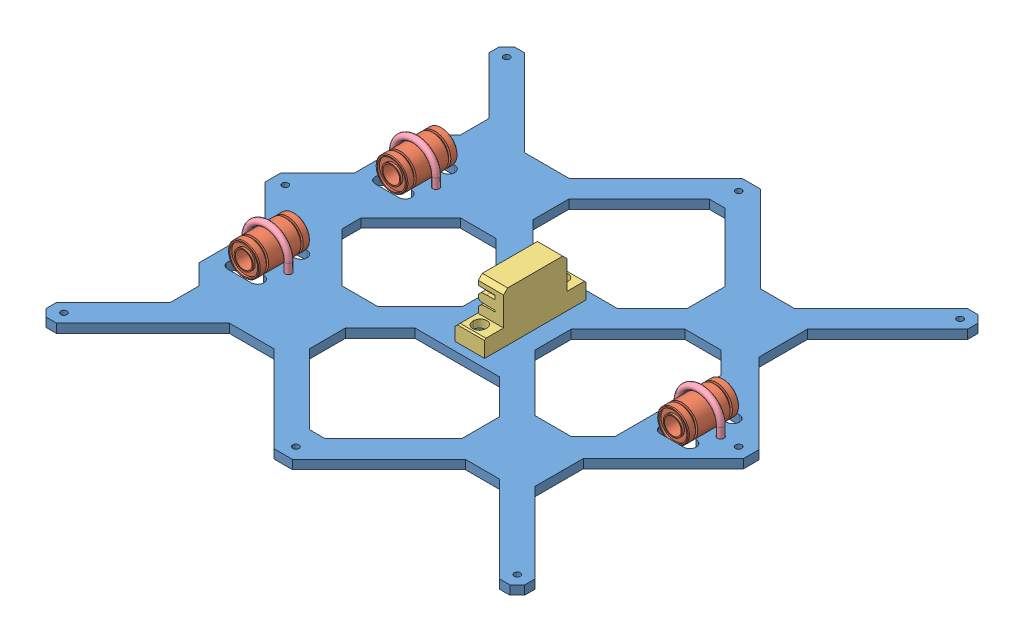
SolidWorks assembly Frog Assembly, configuration Default. Lengths in mm.
Overall size (227 34.1 222).
16 component instances, 6 part files, 37 mates.
Components (placement in the parent):
- i3 MK3 Frog-1: i3 MK3 Frog [Default] at (-100.0918 124.8902 356.7011) size (227 4.25 222)
- LM8UU-1: LM8UU [Default] at (166.4082 134.7303 172.4511) x (0 0 -1) z (0.49499 0.868899 0) size (24 15 15)
- LM8UU-2: LM8UU [Default] at (-3.5918 134.7303 205.9511) x (0 0 -1) z (0.957162 -0.289554 0) size (24 15 15)
- LM8UU-3: LM8UU [Default] at (-3.5918 134.7303 135.9511) x (0 0 -1) z (-0.936768 -0.349951 0) size (24 15 15)
- y-belt-holder-1: y-belt-holder [Default] at (88.4082 141.6402 171.7011) x (0 -1 0) z (-1 0 0) size (23.5 48 14)
- U Bolt-1: U Bolt [Default] at (-3.5918 118.7303 206.7011) size (23 26.7 3.46)
- U Bolt-2: U Bolt [Default] at (166.4082 118.7303 171.7011) size (23 26.7 3.46)
- U Bolt-3: U Bolt [Default] at (-3.5918 118.7303 136.7011) size (23 26.7 3.46)
- M3 Nyloc Nut-7: M3 Nyloc Nut [93625A100] at (156.4082 124.8902 171.7011) x (0.980376 0 -0.197136) z (-0.197136 0 -0.980376) size (5.5 4.1 6.35)
- M3 Nyloc Nut-8: M3 Nyloc Nut [93625A100] at (176.4082 124.8902 171.7011) x (1 0 0) z (0 0 -1) size (5.5 4.1 6.35)
- M3 Nyloc Nut-9: M3 Nyloc Nut [93625A100] at (6.4082 124.8902 136.7011) x (1 0 0) z (0 0 -1) size (5.5 4.1 6.35)
- M3 Nyloc Nut-10: M3 Nyloc Nut [93625A100] at (-13.5918 124.8902 136.7011) x (1 0 0) z (0 0 -1) size (5.5 4.1 6.35)
- M3 Nyloc Nut-11: M3 Nyloc Nut [93625A100] at (-13.5918 124.8902 206.7011) x (1 0 0) z (0 0 -1) size (5.5 4.1 6.35)
- M3 Nyloc Nut-12: M3 Nyloc Nut [93625A100] at (6.4082 124.8902 206.7011) x (1 0 0) z (0 0 -1) size (5.5 4.1 6.35)
- M3-10 Screw-1: M3-10 Screw [93235A313] at (81.4082 121.1402 152.2011) x (1 0 0) z (0 -1 0) size (5.5 5.5 13.58)
- M3-10 Screw-2: M3-10 Screw [93235A313] at (81.4082 121.1402 191.2011) x (0.505601 0 0.862768) z (0 -1 0) size (5.5 5.5 13.58)
Mates (geometry in assembly coordinates):
- Tangent1: tangent: line of i3 MK3 Frog-1 through (161.4082 129.1402 164.9511) axis (0 0 1); cylinder of LM8UU-1 through (166.4082 134.7303 218.1406) axis (0 0 1) radius 7.5
- Tangent2: tangent: line of i3 MK3 Frog-1 through (171.4082 129.1402 164.9511) axis (0 0 1); cylinder of LM8UU-1 through (166.4082 134.7303 218.1406) axis (0 0 1) radius 7.5
- Distance1: distance = 2 mm anti-aligned: plane of LM8UU-1 through (166.4082 134.7303 160.4511) normal (0 0 -1); plane of i3 MK3 Frog-1 through (-100.0918 129.1402 158.4511) normal (0 0 1)
- Tangent3: tangent: line of i3 MK3 Frog-1 through (1.4082 129.1402 199.9511) axis (0 0 1); cylinder of LM8UU-2 through (-3.5918 134.7303 251.6406) axis (0 0 1) radius 7.5
- Tangent4: tangent: line of i3 MK3 Frog-1 through (-8.5918 129.1402 199.9511) axis (0 0 1); cylinder of LM8UU-2 through (-3.5918 134.7303 251.6406) axis (0 0 1) radius 7.5
- Distance2: distance = 2 mm anti-aligned: plane of LM8UU-2 through (-3.5918 134.7303 217.9511) normal (0 0 1); plane of i3 MK3 Frog-1 through (-100.0918 129.1402 219.9511) normal (0 0 -1)
- Tangent5: tangent: line of i3 MK3 Frog-1 through (1.4082 129.1402 129.9511) axis (0 0 1); cylinder of LM8UU-3 through (-3.5918 134.7303 181.6406) axis (0 0 1) radius 7.5
- Tangent7: tangent: line of i3 MK3 Frog-1 through (-8.5918 129.1402 129.9511) axis (0 0 1); cylinder of LM8UU-3 through (-3.5918 134.7303 181.6406) axis (0 0 1) radius 7.5
- Distance3: distance = 2 mm anti-aligned: plane of LM8UU-3 through (-3.5918 134.7303 147.9511) normal (0 0 1); plane of i3 MK3 Frog-1 through (-100.0918 129.1402 149.9511) normal (0 0 -1)
- Coincident1: coincident anti-aligned: plane of i3 MK3 Frog-1 through (-100.0918 129.1402 356.7011) normal (0 1 0); plane of y-belt-holder-1 through (74.4082 129.1402 147.7011) normal (0 -1 0)
- Parallel1: parallel aligned: plane of i3 MK3 Frog-1 through (61.9082 129.1402 356.7011) normal (-1 0 0); plane of y-belt-holder-1 through (74.4082 137.1402 147.7011) normal (-1 0 0)
- Concentric1: concentric aligned: cylinder of i3 MK3 Frog-1 through (81.4082 129.1402 152.2011) axis (0 -1 0) radius 1.5; circle of y-belt-holder-1
- Concentric2: concentric anti-aligned: circle of i3 MK3 Frog-1; cylinder of U Bolt-1 through (-13.5918 133.7303 206.7011) axis (0 -1 0) radius 1.5
- Concentric3: concentric aligned: circle of i3 MK3 Frog-1; cylinder of U Bolt-1 through (6.4082 118.7303 206.7011) axis (0 1 0) radius 1.5
- Tangent9: tangent aligned: cylinder of LM8UU-2 through (-3.5918 134.7303 251.6406) axis (0 0 1) radius 7.5; plane of U Bolt-1 through (-3.5918 142.2303 206.7011) normal (0 1 0)
- Concentric4: concentric anti-aligned: circle of i3 MK3 Frog-1; cylinder of U Bolt-3 through (-13.5918 133.7303 136.7011) axis (0 -1 0) radius 1.5
- Concentric5: concentric aligned: circle of i3 MK3 Frog-1; cylinder of U Bolt-3 through (6.4082 118.7303 136.7011) axis (0 1 0) radius 1.5
- Tangent10: tangent aligned: cylinder of LM8UU-3 through (-3.5918 134.7303 181.6406) axis (0 0 1) radius 7.5; plane of U Bolt-3 through (-3.5918 142.2303 136.7011) normal (0 1 0)
- Concentric6: concentric anti-aligned: circle of i3 MK3 Frog-1; cylinder of U Bolt-2 through (156.4082 133.7303 171.7011) axis (0 -1 0) radius 1.5
- Concentric7: concentric aligned: circle of i3 MK3 Frog-1; cylinder of U Bolt-2 through (176.4082 118.7303 171.7011) axis (0 1 0) radius 1.5
- Tangent11: tangent aligned: cylinder of LM8UU-1 through (166.4082 134.7303 218.1406) axis (0 0 1) radius 7.5; plane of U Bolt-2 through (166.4082 142.2303 171.7011) normal (0 1 0)
- Concentric10: concentric anti-aligned: cylinder of U Bolt-2 through (156.4082 133.7303 171.7011) axis (0 -1 0) radius 1.5; circle of M3 Nyloc Nut-7
- Coincident2: coincident anti-aligned: plane of i3 MK3 Frog-1 through (-100.0918 124.8902 356.7011) normal (0 -1 0); plane of M3 Nyloc Nut-7 through (154.6511 124.8902 176.9129) normal (0 1 0)
- Concentric11: concentric aligned: cylinder of U Bolt-2 through (176.4082 118.7303 171.7011) axis (0 1 0) radius 1.5; circle of M3 Nyloc Nut-8
- Coincident3: coincident anti-aligned: plane of i3 MK3 Frog-1 through (-100.0918 124.8902 356.7011) normal (0 -1 0); plane of M3 Nyloc Nut-8 through (173.6582 124.8902 176.4642) normal (0 1 0)
- Concentric12: concentric aligned: cylinder of U Bolt-1 through (6.4082 118.7303 206.7011) axis (0 1 0) radius 1.5; circle of M3 Nyloc Nut-12
- Concentric13: concentric anti-aligned: cylinder of U Bolt-1 through (-13.5918 133.7303 206.7011) axis (0 -1 0) radius 1.5; circle of M3 Nyloc Nut-11
- Concentric14: concentric anti-aligned: cylinder of U Bolt-3 through (6.4082 118.7303 136.7011) axis (0 1 0) radius 1.5; circle of M3 Nyloc Nut-9
- Concentric15: concentric anti-aligned: cylinder of U Bolt-3 through (-13.5918 133.7303 136.7011) axis (0 -1 0) radius 1.5; circle of M3 Nyloc Nut-10
- Coincident4: coincident anti-aligned: plane of i3 MK3 Frog-1 through (-100.0918 124.8902 356.7011) normal (0 -1 0); plane of M3 Nyloc Nut-11 through (-16.3418 124.8902 211.4642) normal (0 1 0)
- Coincident5: coincident anti-aligned: plane of i3 MK3 Frog-1 through (-100.0918 124.8902 356.7011) normal (0 -1 0); plane of M3 Nyloc Nut-9 through (3.6582 124.8902 141.4642) normal (0 1 0)
- Coincident6: coincident anti-aligned: plane of i3 MK3 Frog-1 through (-100.0918 124.8902 356.7011) normal (0 -1 0); plane of M3 Nyloc Nut-10 through (-16.3418 124.8902 141.4642) normal (0 1 0)
- Coincident7: coincident anti-aligned: plane of i3 MK3 Frog-1 through (-100.0918 124.8902 356.7011) normal (0 -1 0); plane of M3 Nyloc Nut-12 through (3.6582 124.8902 211.4642) normal (0 1 0)
- Concentric16: concentric aligned: circle of i3 MK3 Frog-1; circle of M3-10 Screw-2
- Coincident8: coincident anti-aligned: plane of y-belt-holder-1 through (81.4082 131.1402 191.2011) normal (0 1 0); plane of M3-10 Screw-2 through (81.4082 131.1402 191.2011) normal (0 -1 0)
- Concentric17: concentric aligned: circle of i3 MK3 Frog-1; circle of M3-10 Screw-1
- Coincident9: coincident anti-aligned: plane of y-belt-holder-1 through (81.4082 131.1402 152.2011) normal (0 1 0); plane of M3-10 Screw-1 through (81.4082 131.1402 152.2011) normal (0 -1 0)
